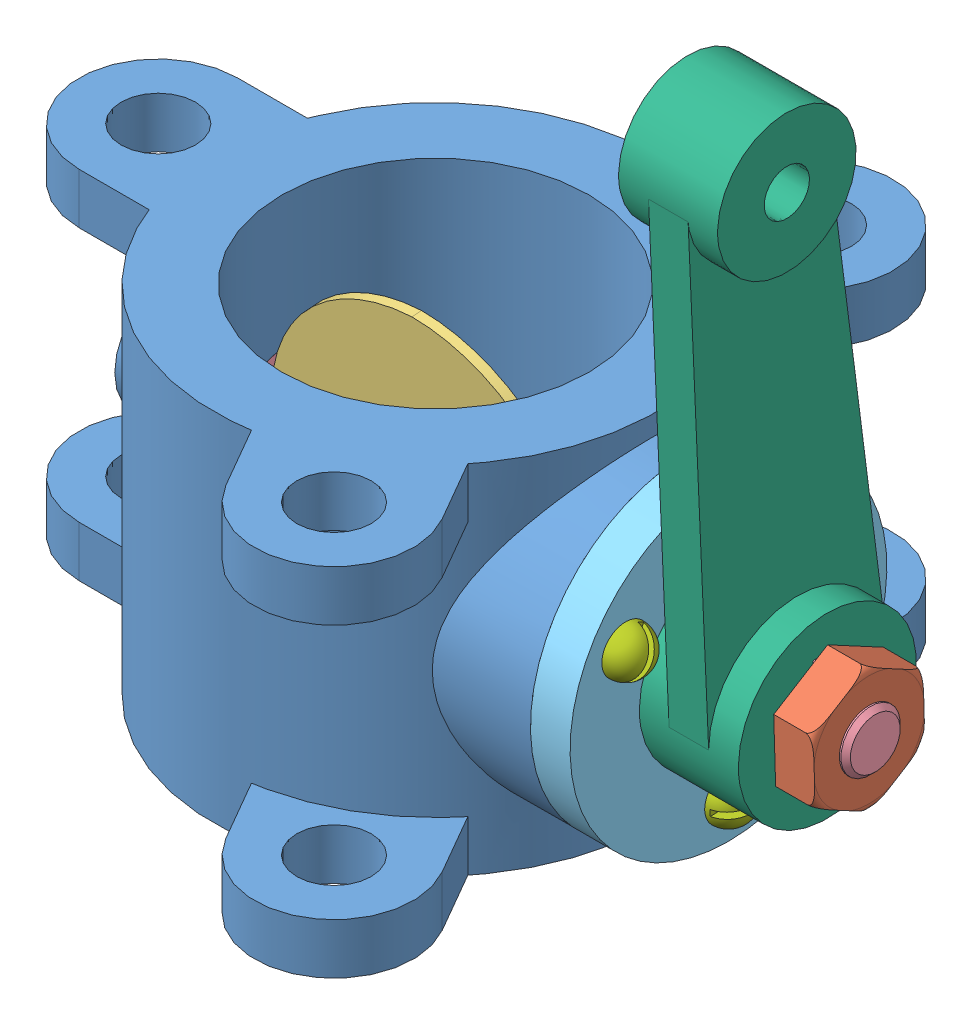
SolidWorks assembly Assem3, configuration Default. Lengths in mm.
Overall size (502.7 459.8 403.11).
9 component instances, 7 part files, 17 mates.
Components (placement in the parent):
- Body-1: Body [Default] at (156.132 303.5099 323.7506) x (-1 0 0) z (0 0 1) size (385 225 403.11)
- Nut-1: Nut [Default] at (404.932 207.0099 323.7506) x (0 0.526045 -0.850457) z (0 -0.850457 -0.526045) size (82.63 26.31 71.91)
- Plate-3: Plate [Default] at (156.032 206.7534 326.7397) x (-1 0 0) z (0 0.99634 0.085476) size (194.11 6 205)
- Shaft-2: Shaft [Default] at (433.832 207.0099 323.7506) x (0 -0.99634 -0.085476) z (0 -0.085476 0.99634) size (87.2 389.8 87.2)
- Retainer-2: Retainer [Default] at (328.632 207.0099 323.7506) x (0 0 -1) z (0 1 0) size (200 25 200)
- Arm-2: Arm [Default] at (372.382 356.4609 336.5721) x (0 0.99634 0.085476) z (0 -0.085476 0.99634) size (400 62.5 112.5)
- Screw-2: Screw [Default] at (303.132 132.0099 323.7506) x (0 0.998812 0.048728) z (-1 0 0) size (30 30 52.87)
- Screw-3: Screw [Default] at (303.132 244.5099 388.7025) x (0 -0.457206 -0.889361) z (-1 0 0) size (30 30 52.87)
- Screw-4: Screw [Default] at (303.132 244.5099 258.7987) x (0 -0.541606 0.840633) z (-1 0 0) size (30 30 52.87)
Mates (geometry in assembly coordinates):
- Concentric8: concentric anti-aligned: cylinder of Body-1 through (324.132 207.0099 323.7506) axis (-1 0 0) radius 28.1; cylinder of Shaft-2 through (252.932 207.0099 323.7506) axis (1 0 0) radius 28
- Coincident14: coincident anti-aligned: plane of Body-1 through (291.132 207.0099 323.7506) normal (1 0 0); plane of Shaft-2 through (291.132 207.0099 323.7506) normal (-1 0 0)
- Concentric9: concentric aligned: cylinder of Plate-3 through (206.032 207.0099 323.7506) axis (0 -0.085476 0.99634) radius 6.25; cylinder of Shaft-2 through (206.032 209.4117 295.7535) axis (0 -0.085476 0.99634) radius 6.25
- Parallel2: parallel aligned: cylinder of Plate-3 through (106.032 207.0099 323.7506) axis (0 -0.085476 0.99634) radius 6.25; cylinder of Shaft-2 through (106.032 209.4117 295.7535) axis (0 -0.085476 0.99634) radius 6.25
- Coincident15: coincident anti-aligned: plane of Plate-3 through (158.913 204.2963 323.5178) normal (0 0.085476 -0.99634); plane of Shaft-2 through (59.132 234.9074 326.144) normal (0 -0.085476 0.99634)
- Concentric11: concentric aligned: cylinder of Plate-3 through (106.032 207.0099 323.7506) axis (0 -0.085476 0.99634) radius 6.25; cylinder of Shaft-2 through (106.032 209.4117 295.7535) axis (0 -0.085476 0.99634) radius 6.25
- Concentric12: concentric aligned: cylinder of Shaft-2 through (315.132 207.0099 323.7506) axis (1 0 0) radius 28; cylinder of Retainer-2 through (316.132 207.0099 323.7506) axis (1 0 0) radius 28
- Concentric13: concentric aligned: cylinder of Body-1 through (250.132 132.0099 323.7506) axis (1 0 0) radius 10.15; cylinder of Retainer-2 through (316.132 132.0099 323.7506) axis (1 0 0) radius 10.15
- Coincident17: coincident anti-aligned: plane of Body-1 through (316.132 207.0099 323.7506) normal (1 0 0); plane of Retainer-2 through (316.132 207.0099 323.7506) normal (-1 0 0)
- Concentric14: concentric anti-aligned: cylinder of Shaft-2 through (315.132 207.0099 323.7506) axis (1 0 0) radius 28; cylinder of Arm-2 through (403.632 207.0099 323.7506) axis (-1 0 0) radius 28.15
- Coincident18: coincident anti-aligned: plane of Retainer-2 through (341.132 207.0099 323.7506) normal (1 0 0); plane of Arm-2 through (341.132 207.0099 323.7506) normal (-1 0 0)
- Concentric15: concentric aligned: cylinder of Nut-1 through (380.932 207.0099 323.7506) axis (1 0 0) radius 18.75; cylinder of Shaft-2 through (404.932 207.0099 323.7506) axis (1 0 0) radius 18.75
- Coincident19: coincident anti-aligned: plane of Nut-1 through (404.932 207.0099 323.7506) normal (-1 0 0); plane of Shaft-2 through (404.932 207.0099 323.7506) normal (1 0 0)
- Concentric16: concentric anti-aligned: cylinder of Retainer-2 through (316.132 132.0099 323.7506) axis (1 0 0) radius 10.15; cylinder of Screw-2 through (303.132 132.0099 323.7506) axis (-1 0 0) radius 10.6066
- Concentric18: concentric aligned: circle of Retainer-2; circle of Screw-2
- Coincident20: coincident anti-aligned: plane of Retainer-2 through (341.132 207.0099 323.7506) normal (1 0 0); plane of Screw-2 through (341.132 142.6039 324.2675) normal (-1 0 0)
- Coincident21: coincident aligned: plane of Shaft-2 through (433.832 207.0099 323.7506) normal (0 -0.085476 0.99634); plane of Arm-2 through (372.382 356.4609 336.5721) normal (0 -0.085476 0.99634)
